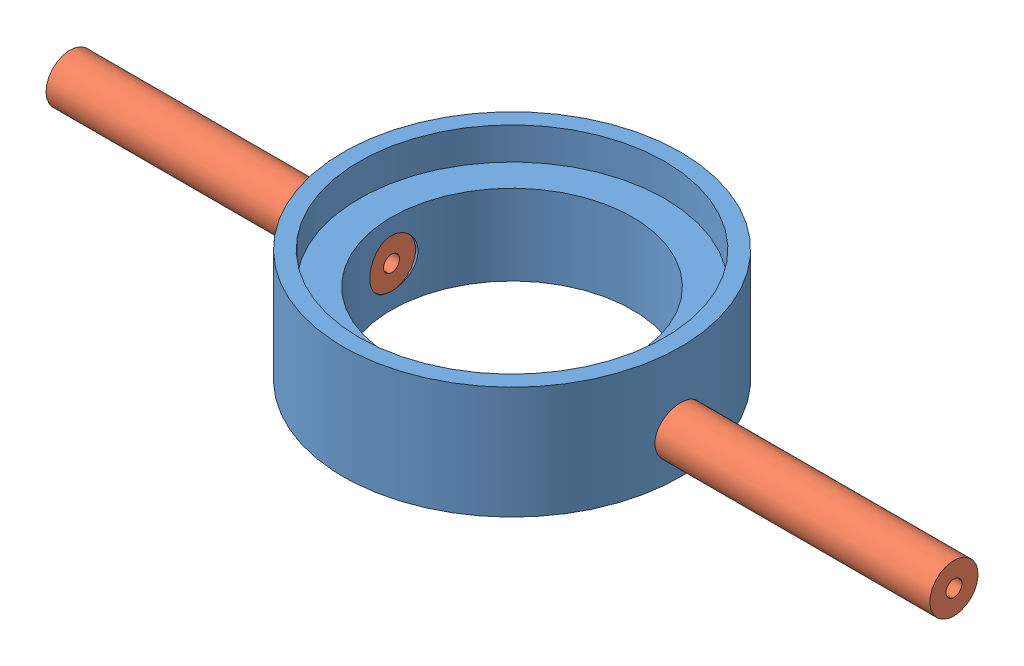
SolidWorks assembly 3Dview-Inner bottom, configuration Default. Lengths in mm.
Overall size (55 6.7 21).
3 component instances, 2 part files, 4 mates.
Components (placement in the parent):
- Inner bottom-1: Inner bottom [Default] at origin size (21 6.7 21)
- 3x1-2: 3x1 [Default] at (-7.5 2.5 0) x (0 0.981723 0.190315) z (-1 0 0) size (3 3 20)
- 3x1-4: 3x1 [Default] at (27.5 2.5 0) x (0 -0.991525 0.129918) z (-1 0 0) size (3 3 20)
Mates (geometry in assembly coordinates):
- Concentrico1: concentric anti-aligned: circle of Inner bottom-1; circle of 3x1-2
- Concentrico2: concentric anti-aligned: circle of Inner bottom-1; circle of 3x1-4
- Tangente1: tangent anti-aligned: cylinder of Inner bottom-1 through (0 0 0) axis (0 1 0) radius 7.5; plane of 3x1-2 through (-7.5 2.5 0) normal (1 0 0)
- Tangente2: tangent anti-aligned: cylinder of Inner bottom-1 through (0 0 0) axis (0 1 0) radius 7.5; plane of 3x1-4 through (7.5 2.5 0) normal (-1 0 0)
